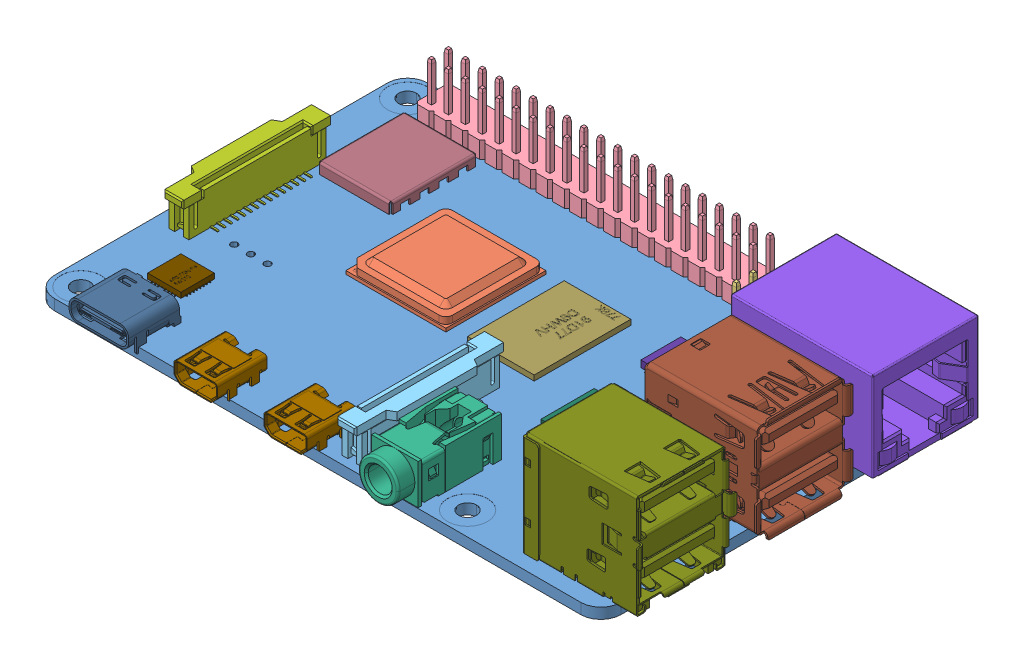
SolidWorks assembly Raspberry Pi 4 Model B, configuration Défaut. Lengths in mm.
Overall size (89 19.92 58.4).
20 component instances, 18 part files, 0 mates.
Components (placement in the parent):
- Raspberry Pi 4 Model B.STEP-1: Raspberry Pi 4 Model B.STEP [Défaut] at origin size (89 19.92 58.4)
  - PCB, RPi4ModelB.STEP-1: PCB, RPi4ModelB.STEP [Défaut] at origin size (85 1.6 56)
  - Broadcom BCM2711B0 CPU, RPi4ModelB.STEP-1: Broadcom BCM2711B0 CPU, RPi4ModelB.STEP [Défaut] at (-13.25 0.8 -4.5) size (15 2.3 15)
  - 2.54 mm DUPONT MALE PIN HEADER, POE, 2X2, RPi4ModelB.STEP-1: 2.54 mm DUPONT MALE PIN HEADER, POE, 2X2, RPi4ModelB.STEP [Défaut] at (19 0.8 -18.36) size (5.08 11.3 5.08)
  - 2.54 mm DUPONT MALE PIN HEADER, IO, 2X20, RPi4ModelB.STEP-1: 2.54 mm DUPONT MALE PIN HEADER, IO, 2X20, RPi4ModelB.STEP [Défaut] at (-10 0.8 -24.5) size (50.8 11.3 5.08)
  - Camera Connector, RPi4ModelB.STEP-1: Camera Connector, RPi4ModelB.STEP [Défaut] at (4 0.8 16.5) x (0 0 -1) z (1 0 0) size (22.4 5.68 5.07)
  - Microphone Plug, RPi4ModelB.STEP-1: Microphone Plug, RPi4ModelB.STEP [Défaut] at (11.5 0.8 21.65) size (7.23 7.55 15)
  - Display Connector, RPi4ModelB.STEP-1: Display Connector, RPi4ModelB.STEP [Défaut] at (-38.5 0.8 0) x (0 0 1) z (-1 0 0) size (22.4 5.68 5.07)
  - Gigabit Ethernet Port, RPi4ModelB.STEP-1: Gigabit Ethernet Port, RPi4ModelB.STEP [Défaut] at (45.5 7.55 -17.75) x (0 0 -1) z (1 0 0) size (16.33 17.24 21.6)
  - Female Micro HDMI Connector, RPi4ModelB.STEP-1: Female Micro HDMI Connector, RPi4ModelB.STEP [Défaut] at (-3 0.8 27.3875) size (6.5 3.51 7.5)
  - Female Micro HDMI Connector, RPi4ModelB.STEP-2: Female Micro HDMI Connector, RPi4ModelB.STEP [Défaut] at (-16.5 0.8 27.3875) size (6.5 3.51 7.5)
  - Female USB Type C Connector, RPi4ModelB.STEP-1: Female USB Type C Connector, RPi4ModelB.STEP [Défaut] at (-31.3 0.8 26.5419) size (8.94 3.96 7.9)
  - 2X USB3.0 PORTS, RPi4ModelB.STEP-1: 2X USB3.0 PORTS, RPi4ModelB.STEP [Défaut] at (37.07 0.8 1) size (17.48 19.42 15.69)
  - 91D77 D9WHV 778K, 4 GB LPDDR4 SDRAM, RPi4ModelB.STEP-1: 91D77 D9WHV 778K, 4 GB LPDDR4 SDRAM, RPi4ModelB.STEP [Défaut] at (2.25 0.8 -4.5) size (10 0.8 14.5)
  - Cypress CYW43455 Wireless Module Cover, RPi4ModelB.STEP-1: Cypress CYW43455 Wireless Module Cover, RPi4ModelB.STEP [Défaut] at (-30.5 0.8 -14.5) size (11 1.6 13)
  - SD Card Slot, RPi4ModelB.STEP-1: SD Card Slot, RPi4ModelB.STEP [Défaut] at (-35.3 -0.8 0) x (0 0 -1) z (-1 0 0) size (11.95 1.45 11.4)
  - VIA VL805 PCIe USB 3.0 controller, RPi4ModelB.STEP-1: VIA VL805 PCIe USB 3.0 controller, RPi4ModelB.STEP [Défaut] at (17.5 0.8 4) size (8.8 0.8 8.8)
  - 2X USB2.0 PORTS, RPi4ModelB.STEP-1: 2X USB2.0 PORTS, RPi4ModelB.STEP [Défaut] at (37.065 0.65 19) size (17.87 19.17 15.35)
  - Broadcom BCM54213PE Gigabit Ethernet Transceiver, RPi4ModelB.STEP-1: Broadcom BCM54213PE Gigabit Ethernet Transceiver, RPi4ModelB.STEP [Défaut] at (16.5 0.8 -10) size (6.8 1 6.8)
  - MxL7704 Universal PMIC, RPi4ModelB.STEP-1: MxL7704 Universal PMIC, RPi4ModelB.STEP [Défaut] at (-32.5 0.8 16) size (5.4 0.8 5.4)
